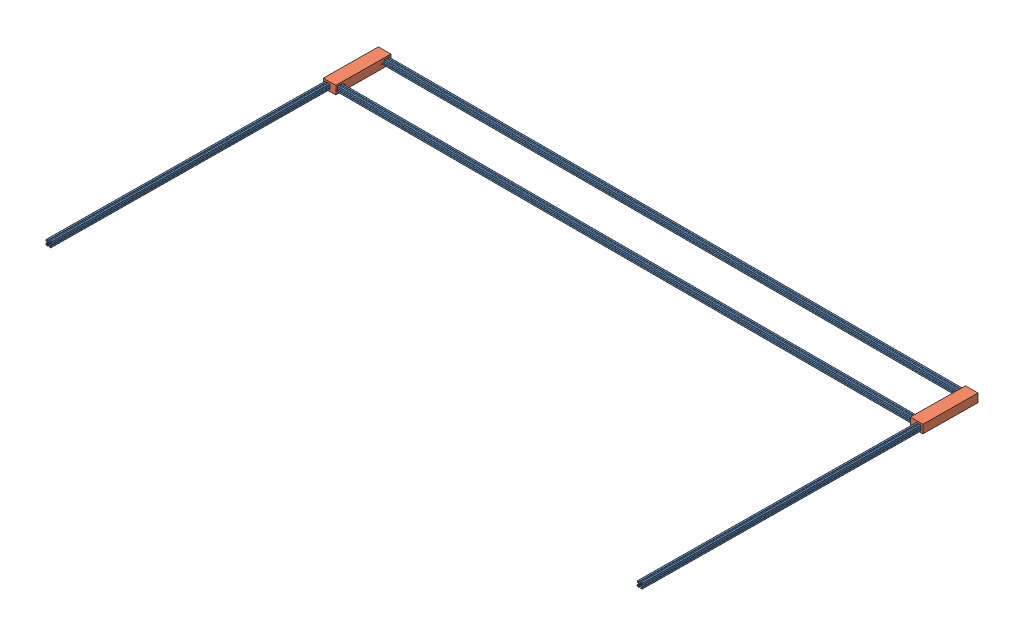
SolidWorks assembly coso referencia gazebo, configuration Predeterminado. Lengths in mm.
Overall size (3590 57.45 2000.27).
6 component instances, 2 part files, 15 mates.
Components (placement in the parent):
- riel-1: riel [Default_New3] at (-54.7927 -931.5425 1819.8096) x (1 0 0) z (0 -0.999962 0.008727) size (30 2000 30)
- soporte vertical-1: soporte vertical [Predeterminado] at (-79.7927 -947.5557 -15.1206) x (0 -0.008727 -0.999962) z (1 0 0) size (330 50 75)
- riel-2: riel [Default_New4] at (3465.2073 -946.334 124.8741) x (0 0.999962 -0.008727) z (0 -0.008727 -0.999962) size (30 3500 30)
- soporte vertical-2: soporte vertical [Predeterminado] at (3510.2073 -947.5557 -15.1206) x (0 0.008727 0.999962) z (-1 0 0) size (330 50 75)
- riel-3: riel [Default_New3] at (3485.2073 -931.5425 1819.8096) x (1 0 0) z (0 -0.999962 0.008727) size (30 2000 30)
- riel-4: riel [Default_New4] at (3465.2073 -948.7774 -155.1152) x (0 0.008727 0.999962) z (0 0.999962 -0.008727) size (30 3500 30)
Mates (geometry in assembly coordinates):
- Coincidente19: coincident anti-aligned: plane of riel-1 through (-59.6927 -963.995 -179.9834) normal (0 -0.999962 0.008727); plane of soporte vertical-1 through (-69.7927 -963.995 -179.9834) normal (0 0.999962 -0.008727)
- Coincidente20: coincident anti-aligned: plane of riel-1 through (-69.7927 -944.0958 -180.157) normal (-1 0 0); plane of soporte vertical-1 through (-69.7927 -933.9962 -180.2452) normal (1 0 0)
- Coincidente21: coincident aligned: plane of riel-1 through (-40.6927 -953.8954 -180.0715) normal (0 -0.008727 -0.999962); plane of soporte vertical-1 through (-4.7927 -973.9946 -179.8961) normal (0 -0.008727 -0.999962)
- Coincidente22: coincident anti-aligned: plane of soporte vertical-1 through (-34.7927 -931.2037 139.7426) normal (0 -0.008727 -0.999962); plane of riel-2 through (-34.7927 -941.3033 139.8308) normal (0 0.008727 0.999962)
- Coincidente23: coincident anti-aligned: plane of soporte vertical-1 through (-34.7927 -947.5557 -15.1206) normal (1 0 0); plane of riel-2 through (-34.7927 -932.2773 119.8512) normal (-1 0 0)
- Coincidente24: coincident anti-aligned: plane of soporte vertical-1 through (-34.7927 -961.2025 140.0044) normal (0 0.999962 -0.008727); plane of riel-2 through (-34.7927 -961.2907 129.9048) normal (0 -0.999962 0.008727)
- Coincidente25: coincident anti-aligned: plane of riel-2 through (-34.7927 -931.2918 129.643) normal (0 0.999962 -0.008727); plane of soporte vertical-2 through (3465.2073 -931.2037 139.7426) normal (0 -0.999962 0.008727)
- Coincidente26: coincident anti-aligned: plane of riel-2 through (3465.2073 -932.2773 119.8512) normal (1 0 0); plane of soporte vertical-2 through (3465.2073 -947.5557 -15.1206) normal (-1 0 0)
- Coincidente27: coincident anti-aligned: plane of riel-2 through (-34.7927 -941.3033 139.8308) normal (0 0.008727 0.999962); plane of soporte vertical-2 through (3465.2073 -931.2037 139.7426) normal (0 -0.008727 -0.999962)
- Coincidente28: coincident anti-aligned: plane of soporte vertical-2 through (3500.2073 -961.1153 150.004) normal (0 0.999962 -0.008727); plane of riel-3 through (3490.1073 -963.995 -179.9834) normal (0 -0.999962 0.008727)
- Coincidente29: coincident anti-aligned: plane of soporte vertical-2 through (3500.2073 -931.1164 149.7422) normal (-1 0 0); plane of riel-3 through (3500.2073 -944.0958 -180.157) normal (1 0 0)
- Coincidente30: coincident aligned: plane of soporte vertical-2 through (3435.2073 -973.9946 -179.8961) normal (0 -0.008727 -0.999962); plane of riel-3 through (3499.3073 -953.8954 -180.0715) normal (0 -0.008727 -0.999962)
- Coincidente31: coincident anti-aligned: plane of soporte vertical-2 through (3465.2073 -963.9078 -169.9838) normal (0 0.999962 -0.008727); plane of riel-4 through (-34.7927 -963.7341 -150.0845) normal (0 -0.999962 0.008727)
- Coincidente32: coincident anti-aligned: plane of soporte vertical-2 through (3465.2073 -947.5557 -15.1206) normal (-1 0 0); plane of riel-4 through (3465.2073 -943.7546 -141.0585) normal (1 0 0)
- Coincidente33: coincident anti-aligned: plane of soporte vertical-2 through (3465.2073 -933.6471 -140.2467) normal (0 -0.008727 -0.999962); plane of riel-4 through (-34.7927 -943.7467 -140.1586) normal (0 0.008727 0.999962)
